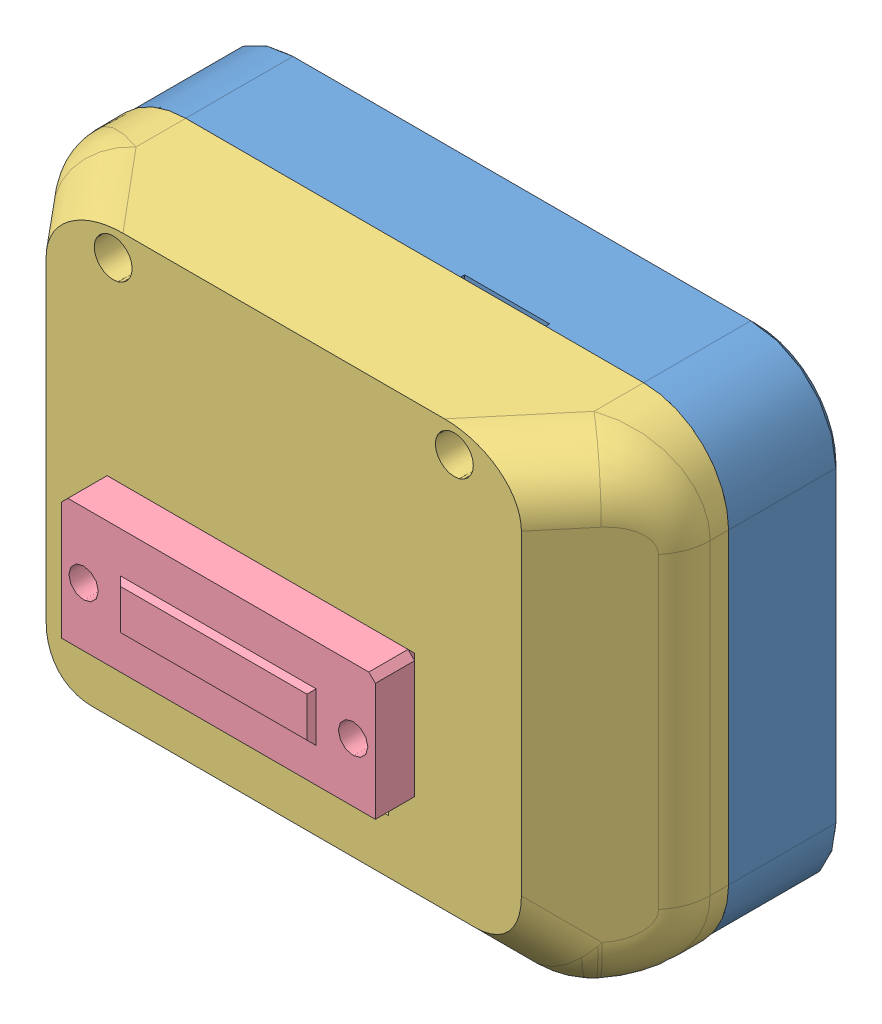
SolidWorks assembly LCD Handcontroller, configuration Default. Lengths in mm.
Overall size (96 73 51.34).
5 component instances, 5 part files, 12 mates.
Components (placement in the parent):
- LCD_case_front-1: LCD_case_front [Default] at (-41.0553 -18.6521 12.8363) size (96 73 17.7)
- LCDKeypadShield.stp-1: LCDKeypadShield.stp [Default] at (-114.0114 -42.2328 65.765) x (0 -1 0) z (0 0 -1) size (58.22 81.01 21.55)
- LCD_Case_back-1: LCD_Case_back [Default] at (-41.0553 -18.6521 30.5365) size (96 73 21.7)
- LCD_base_holder-1: LCD_base_holder [Default] at (-41.0553 -30.5331 50.5365) size (48 20 21.03)
- c4_buttons-1: c4_buttons [Default] at (-23.9671 -43.4629 21.8917) x (-1 0 0) z (0 0 -1) size (40.15 16.41 12)
Mates (geometry in assembly coordinates):
- Parallel1: parallel anti-aligned: plane of case2-1 through (-41.0553 -18.6521 15.8363) normal (0 0 1); plane of LCDKeypadShield.stp-1 through (-90.9772 -55.1848 27.1125) normal (0 0 -1)
- Deckungsgleich2: coincident anti-aligned: plane of case2-1 through (-81.1303 -47.9521 141.8395) normal (0 1 0); plane of LCDKeypadShield.stp-1 through (-78.4503 -47.9521 27.1125) normal (0 -1 0)
- Abstand1: distance = 0.14 mm anti-aligned: plane of case2-1 through (-81.1303 -47.9521 141.8395) normal (1 0 0); plane of LCDKeypadShield.stp-1 through (-80.9903 4.7275 27.1125) normal (-1 0 0)
- Abstand2: distance = 11.2763 mm: plane of case2-1 through (-41.0553 -18.6521 15.8363) normal (0 0 1); point of LCDKeypadShield.stp-1
- Deckungsgleich3: coincident aligned: plane of case2-1 through (-90.9772 -55.1848 30.5365) normal (0 0 1); plane of Lid-1 through (-41.0553 -18.6521 30.5365) normal (0 0 1)
- Deckungsgleich4: coincident aligned: plane of case2-1 through (-41.0553 -18.6521 12.8363) normal (1 0 0); plane of Lid-1 through (-41.0553 -18.6521 30.5365) normal (1 0 0)
- Deckungsgleich5: coincident aligned: plane of case2-1 through (-41.0553 -18.6521 12.8363) normal (0 1 0); plane of Lid-1 through (-41.0553 -18.6521 30.5365) normal (0 1 0)
- Deckungsgleich6: coincident aligned: plane of case2-1 through (-41.0553 -18.6521 12.8363) normal (1 0 0); plane of Halterung-1 through (-41.0553 -30.5331 50.5365) normal (1 0 0)
- Deckungsgleich8: coincident aligned: plane of Lid-1 through (-76.0553 4.8479 50.5365) normal (0 0 1); plane of Halterung-1 through (-41.0553 -30.5331 50.5365) normal (0 0 1)
- Konzentrisch1: concentric aligned: cylinder of case2-1 through (-23.9747 -36.4693 12.8363) axis (0 0 1) radius 2.625; cylinder of c4_buttons-1 through (-23.9747 -36.4693 9.8917) axis (0 0 1) radius 2.35
- Konzentrisch2: concentric aligned: cylinder of case2-1 through (-40.5533 -41.6243 12.8363) axis (0 0 1) radius 2.625; cylinder of c4_buttons-1 through (-40.5533 -41.6243 12.3917) axis (0 0 1) radius 2.35
- Abstand3: distance = 6.5 mm anti-aligned: plane of Lid-1 through (-56.0553 -37.9587 30.5355) normal (0 1 0); plane of Halterung-1 through (-26.5553 -31.4587 50.5365) normal (0 -1 0)
